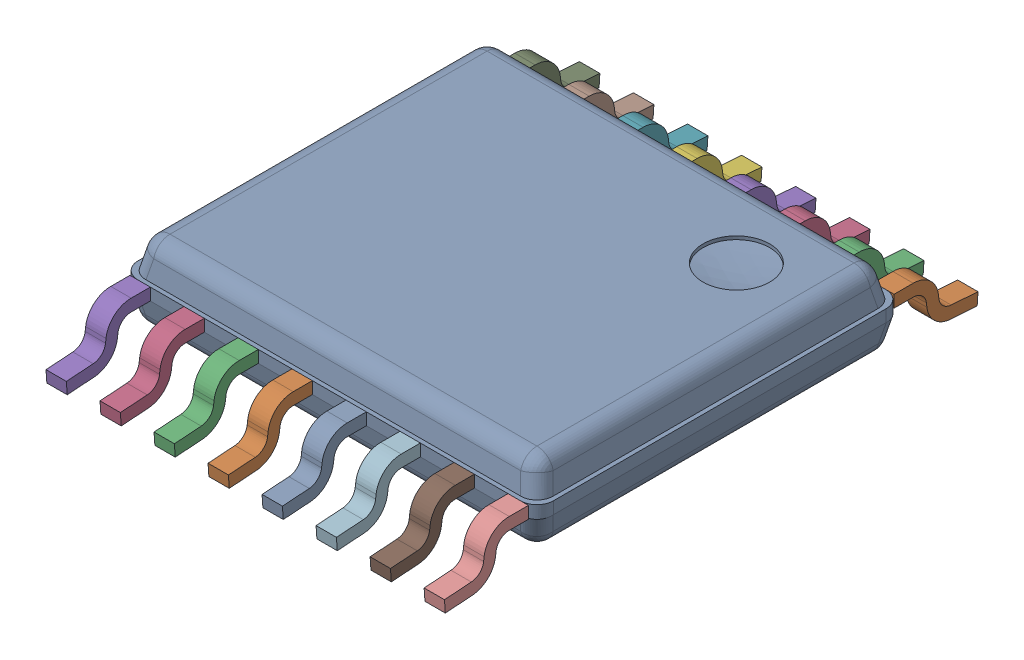
SolidWorks assembly PW0016AakaMTC16, configuration Default. Lengths in mm.
Overall size (5 1 6.42).
17 component instances, 2 part files, 0 mates.
Components (placement in the parent):
- BODY_MTC16-1: BODY_MTC16 [Default] at origin size (5 0.9 4.4)
- LEAD_MTC16-1: LEAD_MTC16 [Default] at (2.275 -0.3725 -2.6) x (-1 0 0) z (0 0 -1) size (0.25 0.62 1.01)
- LEAD_MTC16-2: LEAD_MTC16 [Default] at (1.625 -0.3725 -2.6) x (-1 0 0) z (0 0 -1) size (0.25 0.62 1.01)
- LEAD_MTC16-3: LEAD_MTC16 [Default] at (0.975 -0.3725 -2.6) x (-1 0 0) z (0 0 -1) size (0.25 0.62 1.01)
- LEAD_MTC16-4: LEAD_MTC16 [Default] at (0.325 -0.3725 -2.6) x (-1 0 0) z (0 0 -1) size (0.25 0.62 1.01)
- LEAD_MTC16-5: LEAD_MTC16 [Default] at (-0.325 -0.3725 -2.6) x (-1 0 0) z (0 0 -1) size (0.25 0.62 1.01)
- LEAD_MTC16-6: LEAD_MTC16 [Default] at (-0.975 -0.3725 -2.6) x (-1 0 0) z (0 0 -1) size (0.25 0.62 1.01)
- LEAD_MTC16-7: LEAD_MTC16 [Default] at (-1.625 -0.3725 -2.6) x (-1 0 0) z (0 0 -1) size (0.25 0.62 1.01)
- LEAD_MTC16-8: LEAD_MTC16 [Default] at (-2.275 -0.3725 -2.6) x (-1 0 0) z (0 0 -1) size (0.25 0.62 1.01)
- LEAD_MTC16-9: LEAD_MTC16 [Default] at (2.275 -0.3725 2.6) size (0.25 0.62 1.01)
- LEAD_MTC16-10: LEAD_MTC16 [Default] at (1.625 -0.3725 2.6) size (0.25 0.62 1.01)
- LEAD_MTC16-11: LEAD_MTC16 [Default] at (0.975 -0.3725 2.6) size (0.25 0.62 1.01)
- LEAD_MTC16-12: LEAD_MTC16 [Default] at (0.325 -0.3725 2.6) size (0.25 0.62 1.01)
- LEAD_MTC16-13: LEAD_MTC16 [Default] at (-0.325 -0.3725 2.6) size (0.25 0.62 1.01)
- LEAD_MTC16-14: LEAD_MTC16 [Default] at (-0.975 -0.3725 2.6) size (0.25 0.62 1.01)
- LEAD_MTC16-15: LEAD_MTC16 [Default] at (-1.625 -0.3725 2.6) size (0.25 0.62 1.01)
- LEAD_MTC16-16: LEAD_MTC16 [Default] at (-2.275 -0.3725 2.6) size (0.25 0.62 1.01)
